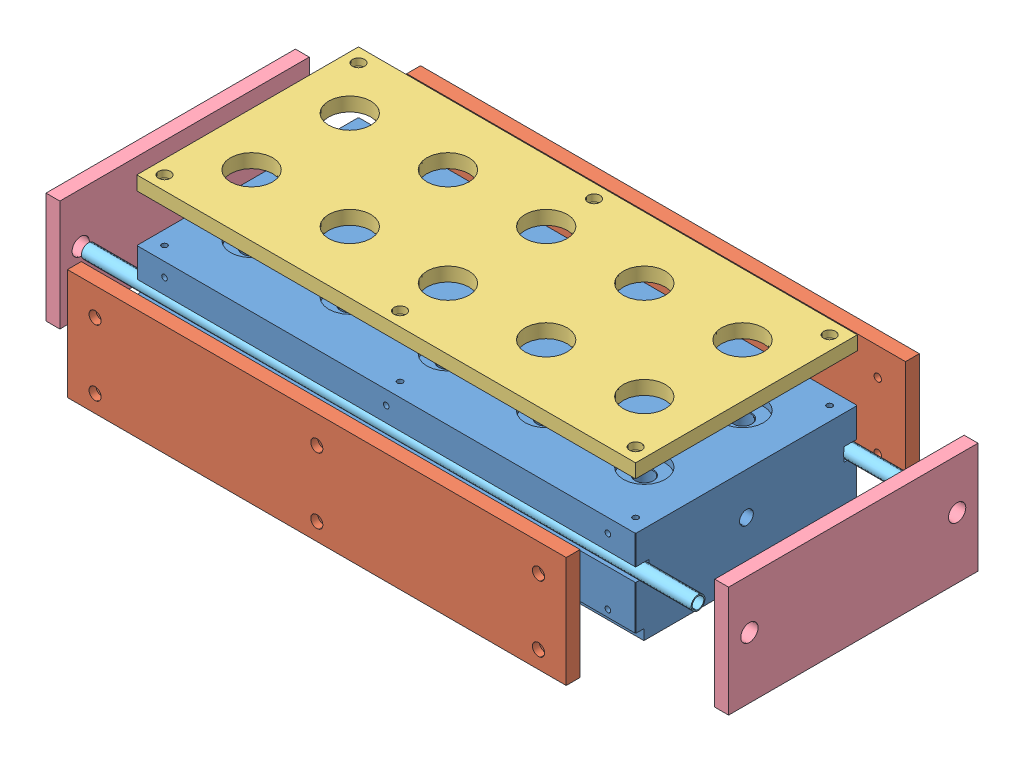
SolidWorks assembly htrblockassem2, configuration Default. Lengths in mm.
Overall size (625.65 144.98 323.67).
8 component instances, 5 part files, 19 mates.
Components (placement in the parent):
- heatblk1-1: heatblk1 [Default] at origin size (457.2 88.9 203.2)
- sideinsul1-1: sideinsul1 [Default] at (0 -50.8 165.1945) x (1 0 0) z (0 -1 0) size (457.2 12.7 101.6)
- sideinsul1-2: sideinsul1 [Default] at (0 -50.8 -158.4782) x (-1 0 0) z (0 -1 0) size (457.2 12.7 101.6)
- topinsul1-1: topinsul1 [Default] at (0 43.383 0) size (457.2 12.7 203.2)
- endisul1-1: endisul1 [Default] at (326.5326 -50.8 0) size (12.7 101.6 228.6)
- endisul1-2: endisul1 [Default] at (-286.4171 -50.8 0) size (12.7 101.6 228.6)
- cooltube1-1: cooltube1 [Default] at (279.4 -45.5295 95.1865) size (558.8 12.7 12.7)
- cooltube1-2: cooltube1 [Default] at (279.4 -45.5295 -95.1865) size (558.8 12.7 12.7)
Mates (geometry in assembly coordinates):
- Coincident1: coincident aligned: plane of heatblk1-1 through (228.6 -101.6 -101.6) normal (1 0 0); plane of topinsul1-1 through (228.6 30.683 -101.6) normal (1 0 0)
- Coincident2: coincident aligned: plane of heatblk1-1 through (228.6 -101.6 101.6) normal (0 0 1); plane of topinsul1-1 through (228.6 30.683 101.6) normal (0 0 1)
- Coincident3: coincident aligned: plane of sideinsul1-2 through (228.6 0 -145.7782) normal (1 0 0); plane of topinsul1-1 through (228.6 30.683 -101.6) normal (1 0 0)
- Coincident4: coincident aligned: plane of heatblk1-1 through (0 -101.6 0) normal (0 -1 0); plane of sideinsul1-2 through (-228.6 -101.6 -145.7782) normal (0 -1 0)
- Coincident5: coincident aligned: plane of sideinsul1-1 through (228.6 -101.6 152.4945) normal (0 -1 0); plane of heatblk1-1 through (0 -101.6 0) normal (0 -1 0)
- Coincident8: coincident aligned: plane of heatblk1-1 through (228.6 -101.6 -101.6) normal (1 0 0); plane of sideinsul1-1 through (228.6 0 152.4945) normal (1 0 0)
- Coincident9: coincident aligned: plane of heatblk1-1 through (0 -101.6 0) normal (0 -1 0); plane of endisul1-1 through (313.8326 -101.6 -114.3) normal (0 -1 0)
- Coincident10: coincident aligned: plane of heatblk1-1 through (0 -101.6 0) normal (0 -1 0); plane of endisul1-2 through (-299.1171 -101.6 -114.3) normal (0 -1 0)
- Coincident11: coincident aligned: plane of endisul1-1 through (313.8326 0 -114.3) normal (0 0 -1); plane of endisul1-2 through (-299.1171 0 -114.3) normal (0 0 -1)
- Width1: width anti-aligned: plane of endisul1-2 through (-299.1171 0 -114.3) normal (0 0 -1); plane of heatblk1-1 through (-299.1171 0 114.3) normal (0 0 1); plane of endisul1-2 through (228.6 -101.6 101.6) normal (0 0 1); plane of heatblk1-1 through (228.6 -101.6 -101.6) normal (0 0 -1)
- Concentric1: concentric aligned: cylinder of endisul1-1 through (228.599 -45.5295 95.1865) axis (1 0 0) radius 7.9375; cylinder of cooltube1-1 through (-279.4 -45.5295 95.1865) axis (1 0 0) radius 6.35
- Concentric2: concentric anti-aligned: circle of endisul1-1; cylinder of cooltube1-2 through (-279.4 -45.5295 -95.1865) axis (1 0 0) radius 6.35
- Width2: width anti-aligned: plane of cooltube1-1 through (279.4 -45.5295 95.1865) normal (1 0 0); plane of cooltube1-1 through (-279.4 -45.5295 95.1865) normal (-1 0 0); plane of heatblk1-1 through (-228.6 -101.6 -101.6) normal (-1 0 0); plane of heatblk1-1 through (228.6 -101.6 -101.6) normal (1 0 0)
- Coincident12: coincident aligned: plane of cooltube1-1 through (279.4 -45.5295 95.1865) normal (1 0 0); plane of cooltube1-2 through (279.4 -45.5295 -95.1865) normal (1 0 0)
- Coincident13: coincident anti-aligned: plane of heatblk1-1 through (228.6 -12.7 -127.8007) normal (0 1 0); plane of topinsul1-1 through (0 -12.7 0) normal (0 -1 0)
- Coincident14: coincident anti-aligned: plane of heatblk1-1 through (228.6 -101.6 -101.6) normal (1 0 0); plane of endisul1-1 through (228.6 -50.8 0) normal (-1 0 0)
- Coincident16: coincident anti-aligned: plane of heatblk1-1 through (228.6 -101.6 101.6) normal (0 0 1); plane of sideinsul1-1 through (0 -50.8 101.6) normal (0 0 -1)
- Coincident17: coincident anti-aligned: plane of heatblk1-1 through (228.6 -101.6 -101.6) normal (0 0 -1); plane of sideinsul1-2 through (0 -50.8 -101.6) normal (0 0 1)
- Coincident18: coincident anti-aligned: plane of heatblk1-1 through (-228.6 -101.6 -101.6) normal (-1 0 0); plane of endisul1-2 through (-228.6 -50.8 0) normal (1 0 0)
